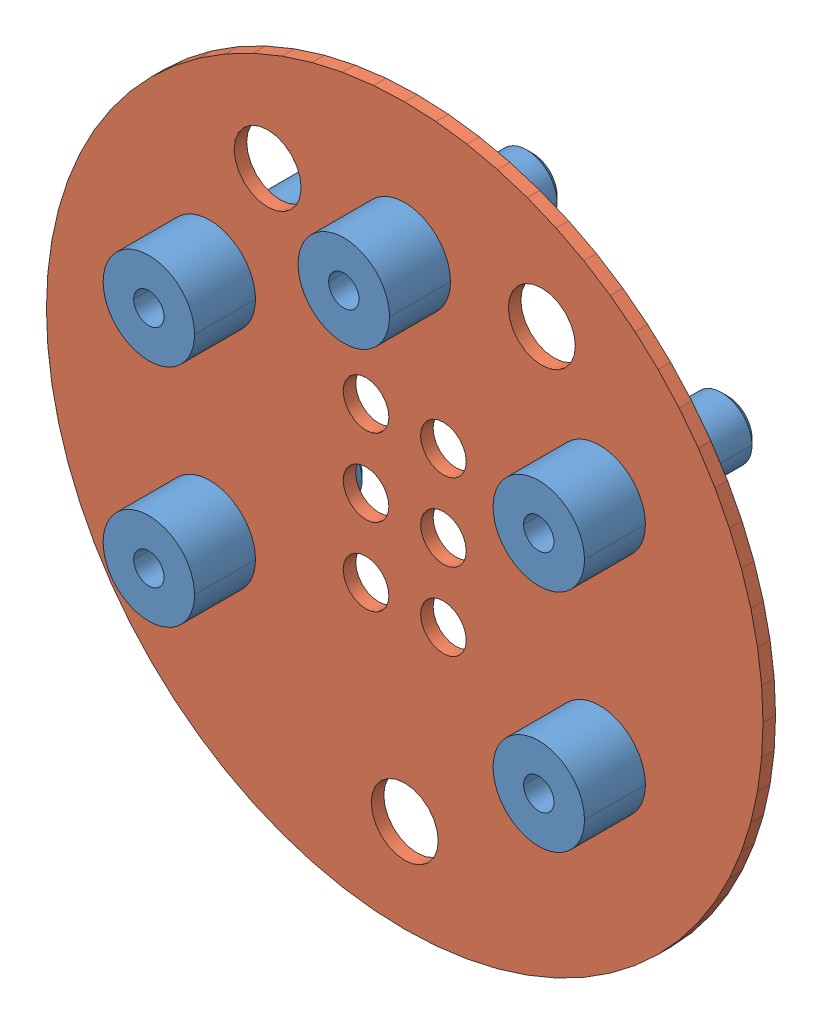
SolidWorks assembly 传感器插座板.step, configuration Default. Lengths in mm.
Overall size (23.52 23.52 6.2).
7 component instances, 2 part files, 0 mates.
Components (placement in the parent):
- JP2^传感器插座板.step-1: JP2^传感器插座板.step [Default] at origin size (15.8 14.1 6.2) (virtual)
  - __________^JP2_传感器插座板.step-1: __________^JP2_传感器插座板.step [Default] at (-6.3999 3.7001 0) size (3 3 6.2) (virtual)
  - __________^JP2_传感器插座板.step-2: __________^JP2_传感器插座板.step [Default] at (6.4001 -3.7 0) size (3 3 6.2) (virtual)
  - __________^JP2_传感器插座板.step-3: __________^JP2_传感器插座板.step [Default] at (-6.3999 -3.6999 0) size (3 3 6.2) (virtual)
  - __________^JP2_传感器插座板.step-4: __________^JP2_传感器插座板.step [Default] at (6.4001 3.7001 0) size (3 3 6.2) (virtual)
  - __________^JP2_传感器插座板.step-5: __________^JP2_传感器插座板.step [Default] at (0.0001 7.4001 0) size (3 3 6.2) (virtual)
- Board.step-1: Board.step [Default] at (0 0 -0.4115) size (23.52 23.52 0.41)
